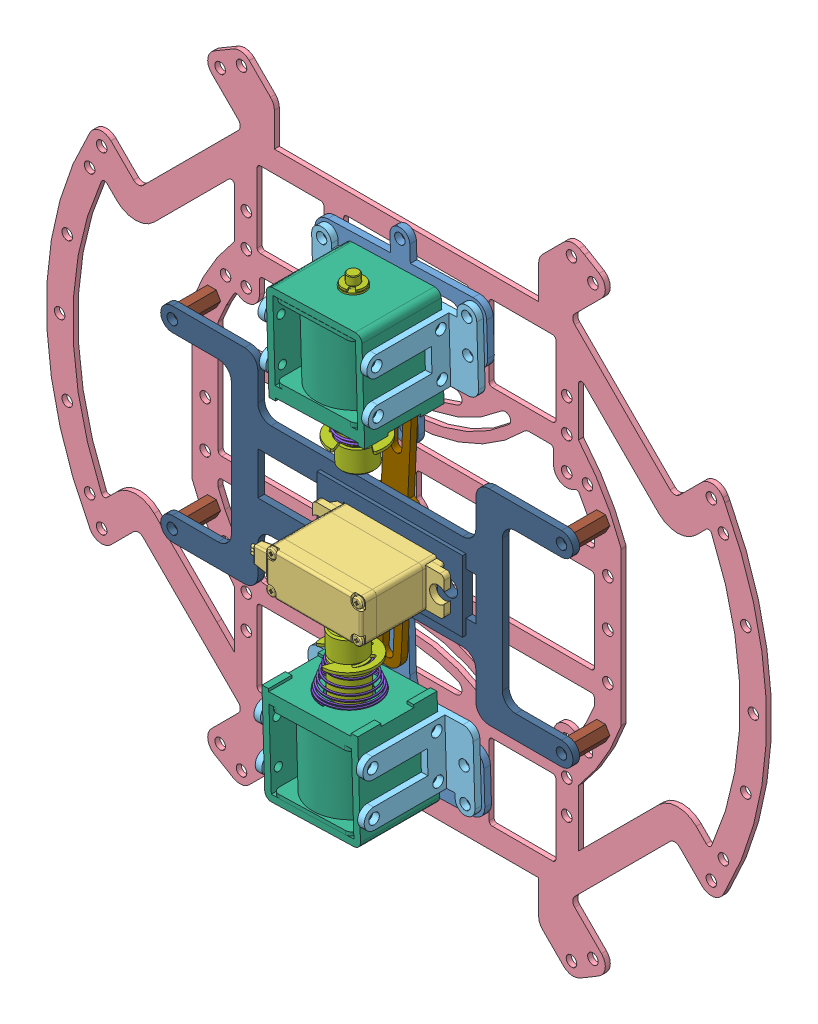
SolidWorks assembly Aimbot-S Test, configuration Default. Lengths in mm.
Overall size (218 192.21 37.61).
21 component instances, 11 part files, 45 mates.
Components (placement in the parent):
- Aimbot Swing-1: Aimbot Swing [Default] at (65.0684 191.5331 171.8045) x (0.999536 0.030468 0) z (0.030468 -0.999536 0) size (52 2 56)
- Sero Adaptor-4: Sero Adaptor [Default] at (64.9466 122.5312 173.8045) x (0.047484 0.998872 0) z (-0.998872 0.047484 0) size (9.1 5 34)
- Servo 2-2: Servo 2 [Default] at (58.4466 116.1312 207.9045) x (1 0 0) z (0 1 0) size (41.92 34.11 12.86)
- Aimbot Mid-1: Aimbot Mid [Default] at (64.9466 122.5312 170.3045) size (218 192.21 1.5)
- CB1029 Kicker Stand-1: CB1029 Kicker Stand [Default] at (49.6459 75.5772 197.7045) x (0 0 -1) z (-0.999536 -0.030468 0) size (26.9 23.5 50)
- CB1029 Kicker Stand-2: CB1029 Kicker Stand [Default] at (80.2472 169.4853 197.7045) x (0 0 -1) z (0.999536 0.030468 0) size (26.9 23.5 50)
- INPUT kicker-3: INPUT kicker [Default] at (61.4457 70.5378 188.2528) x (0.999536 0.030468 0) z (0 0 1) size (29 49.3 24.1)
  - Part5^w_cb1029A-1: Part5^w_cb1029A [Default] at (2.8592 11.2966 11.7516) size (29 29.6 24.1)
  - Part1^w_cb1029A_pl-1: Part1^w_cb1029A_pl [Default] at (2.8592 29.7903 -0.2484) x (-0.794223 0 -0.607626) z (0 1 0) size (16 14.34 49.3)
  - w_21053081-1: w_21053081 [Default] at (2.8631 13.1716 -0.3303) size (16.55 9.4 16.57)
- INPUT kicker-4: INPUT kicker [Default] at (68.4474 174.5247 188.2528) x (-0.999536 -0.030468 0) z (0 0 1) size (29 49.3 24.1)
  - Part5^w_cb1029A-1: Part5^w_cb1029A [Default] at (2.8592 11.2966 11.7516) size (29 29.6 24.1)
  - Part1^w_cb1029A_pl-1: Part1^w_cb1029A_pl [Default] at (2.8592 29.7903 -0.2484) x (-0.794223 0 -0.607626) z (0 1 0) size (16 14.34 49.3)
  - w_21053081-1: w_21053081 [Default] at (2.8631 13.1716 -0.3303) size (16.55 9.4 16.57)
- Aimbot Lever-2: Aimbot Lever [Default] at (66.6085 157.4918 173.8045) x (-0.047484 -0.998872 0) z (-0.998872 0.047484 0) size (78 2 32)
- Aimbot Swing-4: Aimbot Swing [Default] at (64.8247 53.5294 171.8045) x (-0.999536 -0.030468 0) z (-0.030468 0.999536 0) size (52 2 56)
- Servo Stand-1: Servo Stand [Default] at (6.0347 95.0602 181.8045) size (124.82 61.94 3)
- 10mm Standoff-1: 10mm Standoff [默认] at (123.8585 150.0023 171.8045) x (1 0 0) z (0 -1 0) size (5.31 10 4.6)
- 10mm Standoff-2: 10mm Standoff [默认] at (123.8585 95.0602 171.8045) x (1 0 0) z (0 -1 0) size (5.31 10 4.6)
- 10mm Standoff-3: 10mm Standoff [默认] at (6.0347 150.0023 171.8045) x (1 0 0) z (0 -1 0) size (5.31 10 4.6)
- 10mm Standoff-4: 10mm Standoff [默认] at (6.0347 95.0602 171.8045) x (1 0 0) z (0 -1 0) size (5.31 10 4.6)
Mates (geometry in assembly coordinates):
- Coincident15: coincident anti-aligned: plane of Sero Adaptor-4 through (79.4302 121.8427 173.8045) normal (0 0 1); plane of Servo 2-2 through (62.1259 125.3519 173.8045) normal (0 0 -1)
- Concentric35: concentric anti-aligned: cylinder of Servo 2-2 through (64.9466 122.5312 179.1045) axis (0 0 -1) radius 0.925; cylinder of Aimbot Mid-1 through (64.9466 122.5312 50.2343) axis (0 0 1) radius 1.6
- Concentric36: concentric aligned: cylinder of Aimbot Swing-1 through (64.9466 195.5312 168.3045) axis (0 0 1) radius 1.6; cylinder of Aimbot Mid-1 through (64.9466 195.5312 170.3045) axis (0 0 1) radius 1.5
- Coincident17: coincident anti-aligned: plane of Aimbot Swing-1 through (65.0684 191.5331 173.8045) normal (0 0 1); plane of CB1029 Kicker Stand-2 through (80.3386 166.4867 173.8045) normal (0 0 -1)
- Coincident20: coincident anti-aligned: plane of Aimbot Swing-1 through (65.0684 191.5331 171.8045) normal (0 0 -1); plane of Aimbot Mid-1 through (64.9466 122.5312 171.8045) normal (0 0 1)
- Coincident21: coincident anti-aligned: plane of CB1029 Kicker Stand-2 through (51.2607 168.6018 197.7045) normal (0.999536 0.030468 0); plane of INPUT kicker-4/Part5^w_cb1029A-1 through (50.6818 187.5929 176.0045) normal (-0.999536 -0.030468 0)
- Concentric45: concentric aligned: cylinder of CB1029 Kicker Stand-2 through (81.8502 182.5402 178.3045) axis (-0.999536 -0.030468 0) radius 1.6; cylinder of INPUT kicker-4/Part5^w_cb1029A-1 through (79.8512 182.4793 178.3045) axis (-0.999536 -0.030468 0) radius 1.25
- Concentric46: concentric aligned: cylinder of CB1029 Kicker Stand-2 through (82.2463 169.5463 197.7045) axis (-0.999536 -0.030468 0) radius 1.6; cylinder of INPUT kicker-4/Part5^w_cb1029A-1 through (80.2472 169.4853 197.7045) axis (-0.999536 -0.030468 0) radius 1.25
- Coincident22: coincident anti-aligned: plane of CB1029 Kicker Stand-1 through (78.6325 76.4607 197.7045) normal (-0.999536 -0.030468 0); plane of INPUT kicker-3/Part5^w_cb1029A-1 through (79.2113 57.4695 176.0045) normal (0.999536 0.030468 0)
- Concentric47: concentric aligned: cylinder of CB1029 Kicker Stand-1 through (48.0429 62.5223 197.7045) axis (0.999536 0.030468 0) radius 1.6; cylinder of INPUT kicker-3/Part5^w_cb1029A-1 through (50.042 62.5832 197.7045) axis (0.999536 0.030468 0) radius 1.25
- Concentric48: concentric aligned: cylinder of CB1029 Kicker Stand-1 through (47.6468 75.5162 178.3045) axis (0.999536 0.030468 0) radius 1.6; cylinder of INPUT kicker-3/Part5^w_cb1029A-1 through (49.6459 75.5772 178.3045) axis (0.999536 0.030468 0) radius 1.25
- Concentric49: concentric aligned: cylinder of Aimbot Swing-1 through (87.2106 187.2057 173.8045) axis (0 0 -1) radius 1.6; cylinder of CB1029 Kicker Stand-2 through (87.2106 187.2057 183.8045) axis (0 0 -1) radius 1.6
- Concentric50: concentric aligned: cylinder of Aimbot Swing-1 through (43.231 185.8651 173.8045) axis (0 0 -1) radius 1.6; cylinder of CB1029 Kicker Stand-2 through (43.231 185.8651 183.8045) axis (0 0 -1) radius 1.6
- Concentric51: concentric aligned: cylinder of Aimbot Swing-1 through (43.5357 175.8698 173.8045) axis (0 0 -1) radius 1.6; cylinder of CB1029 Kicker Stand-2 through (43.5357 175.8698 183.8045) axis (0 0 -1) radius 1.6
- Concentric52: concentric aligned: cylinder of Aimbot Swing-1 through (87.5152 177.2103 173.8045) axis (0 0 -1) radius 1.6; cylinder of CB1029 Kicker Stand-2 through (87.5152 177.2103 183.8045) axis (0 0 -1) radius 1.6
- Concentric57: concentric aligned: cylinder of Sero Adaptor-4 through (78.9308 121.8665 171.8045) axis (0 0 1) radius 0.5; cylinder of Aimbot Lever-2 through (78.9308 121.8665 91.3423) axis (0 0 1) radius 0.5
- Concentric58: concentric aligned: cylinder of Sero Adaptor-4 through (74.4359 122.0801 171.8045) axis (0 0 1) radius 0.5; cylinder of Aimbot Lever-2 through (74.4359 122.0801 91.3423) axis (0 0 1) radius 0.5
- Coincident24: coincident anti-aligned: plane of Aimbot Swing-1 through (65.0684 191.5331 173.8045) normal (0 0 1); plane of Aimbot Lever-2 through (66.6085 157.4918 173.8045) normal (0 0 -1)
- Concentric59: concentric aligned: cylinder of Aimbot Mid-1 through (64.9466 122.5312 50.2343) axis (0 0 1) radius 1.6; cylinder of Aimbot Lever-2 through (64.9466 122.5312 148.3486) axis (0 0 1) radius 5
- Coincident25: coincident anti-aligned: plane of Sero Adaptor-4 through (79.4302 121.8427 173.8045) normal (0 0 1); plane of Aimbot Lever-2 through (66.6085 157.4918 173.8045) normal (0 0 -1)
- Parallel1: parallel anti-aligned: plane of Sero Adaptor-4 through (79.4302 121.8427 171.8045) normal (0 0 -1); plane of Aimbot Mid-1 through (64.9466 122.5312 171.8045) normal (0 0 1)
- Coincident28: coincident anti-aligned: plane of Aimbot Mid-1 through (64.9466 122.5312 171.8045) normal (0 0 1); plane of Aimbot Swing-4 through (64.8247 53.5294 171.8045) normal (0 0 -1)
- Concentric60: concentric aligned: cylinder of CB1029 Kicker Stand-1 through (42.6826 57.8568 183.8045) axis (0 0 -1) radius 1.6; cylinder of Aimbot Swing-4 through (42.6826 57.8568 173.8045) axis (0 0 -1) radius 1.6
- Concentric61: concentric aligned: cylinder of CB1029 Kicker Stand-1 through (86.6622 59.1973 183.8045) axis (0 0 -1) radius 1.6; cylinder of Aimbot Swing-4 through (86.6622 59.1973 173.8045) axis (0 0 -1) radius 1.6
- Concentric62: concentric aligned: cylinder of Aimbot Mid-1 through (64.9466 49.5312 170.3045) axis (0 0 1) radius 1.5; cylinder of Aimbot Swing-4 through (64.9466 49.5312 168.3045) axis (0 0 1) radius 1.6
- Coincident29: coincident anti-aligned: plane of Aimbot Mid-1 through (64.9466 122.5312 171.8045) normal (0 0 1); plane of Aimbot Swing-4 through (64.8247 53.5294 171.8045) normal (0 0 -1)
- Concentric63: concentric aligned: cylinder of CB1029 Kicker Stand-1 through (86.6622 59.1973 183.8045) axis (0 0 -1) radius 1.6; cylinder of Aimbot Swing-4 through (86.6622 59.1973 173.8045) axis (0 0 -1) radius 1.6
- Concentric64: concentric aligned: cylinder of CB1029 Kicker Stand-1 through (86.3575 69.1927 183.8045) axis (0 0 -1) radius 1.6; cylinder of Aimbot Swing-4 through (86.3575 69.1927 173.8045) axis (0 0 -1) radius 1.6
- Coincident30: coincident anti-aligned: circle of Aimbot Mid-1; cylinder of Servo Stand-1 through (123.8585 150.0023 183.8045) axis (0 0 -1) radius 1.6
- Coincident31: coincident aligned: circle of Aimbot Mid-1; cylinder of Servo Stand-1 through (123.8585 95.0602 183.8045) axis (0 0 -1) radius 1.6
- Concentric65: concentric anti-aligned: cylinder of Aimbot Mid-1 through (6.0347 95.0602 170.3045) axis (0 0 1) radius 1.6; cylinder of Servo Stand-1 through (6.0347 95.0602 183.8045) axis (0 0 -1) radius 1.6
- Parallel2: parallel aligned: cylinder of Aimbot Mid-1 through (3.9986 136.531 171.8045) axis (0 0 -1) radius 1.6; cylinder of Servo Stand-1 through (6.0347 150.0023 183.8045) axis (0 0 -1) radius 1.6
- Parallel3: parallel anti-aligned: cylinder of Servo 2-2 through (90.9279 122.5312 188.3045) axis (0 0 -1) radius 2.5; cylinder of Servo Stand-1 through (90.9266 122.5312 153.6442) axis (0 0 1) radius 2.5
- Concentric68: concentric anti-aligned: cylinder of Servo 2-2 through (54.8653 122.5312 188.3045) axis (0 0 -1) radius 2.5; cylinder of Servo Stand-1 through (54.8656 122.5312 173.8045) axis (0 0 1) radius 2.5
- Coincident34: coincident anti-aligned: plane of Servo 2-2 through (87.0535 116.7167 184.8045) normal (0 0 -1); plane of Servo Stand-1 through (6.0347 95.0602 184.8045) normal (0 0 1)
- Coincident35: coincident anti-aligned: plane of Servo Stand-1 through (6.0347 95.0602 181.8045) normal (0 0 -1); plane of 10mm Standoff-3 through (6.0347 150.0023 181.8045) normal (0 0 1)
- Concentric69: concentric aligned: cylinder of Servo Stand-1 through (6.0347 150.0023 183.8045) axis (0 0 -1) radius 1.6; cylinder of 10mm Standoff-3 through (6.0347 150.0023 176.8045) axis (0 0 -1) radius 1.5
- Coincident36: coincident anti-aligned: plane of Servo Stand-1 through (6.0347 95.0602 181.8045) normal (0 0 -1); plane of 10mm Standoff-4 through (6.0347 95.0602 181.8045) normal (0 0 1)
- Concentric70: concentric aligned: cylinder of Servo Stand-1 through (6.0347 95.0602 183.8045) axis (0 0 -1) radius 1.6; cylinder of 10mm Standoff-4 through (6.0347 95.0602 176.8045) axis (0 0 -1) radius 1.5
- Coincident37: coincident anti-aligned: plane of Servo Stand-1 through (6.0347 95.0602 181.8045) normal (0 0 -1); plane of 10mm Standoff-2 through (123.8585 95.0602 181.8045) normal (0 0 1)
- Concentric71: concentric aligned: cylinder of Servo Stand-1 through (123.8585 95.0602 183.8045) axis (0 0 -1) radius 1.6; cylinder of 10mm Standoff-2 through (123.8585 95.0602 176.8045) axis (0 0 -1) radius 1.5
- Coincident38: coincident: plane of Servo Stand-1 through (6.0347 95.0602 181.8045) normal (0 0 -1); line of 10mm Standoff-1 through (122.5306 147.7023 181.8045) axis (1 0 0)
- Concentric72: concentric aligned: cylinder of Servo Stand-1 through (123.8585 150.0023 183.8045) axis (0 0 -1) radius 1.6; cylinder of 10mm Standoff-1 through (123.8585 150.0023 176.8045) axis (0 0 -1) radius 1.5
- Slot1: slot aligned: cylinder of Aimbot Swing-1 through (66.3024 151.0519 181.8045) axis (0 0 -1) radius 1.6; plane of Aimbot Lever-2 through (67.4945 142.4327 185.8045) normal (-0.998872 0.047484 0); cylinder of Aimbot Lever-2 through (66.6085 157.4918 185.8045) axis (0 0 -1) radius 1.6
- Slot2: slot aligned: cylinder of Aimbot Swing-4 through (63.5908 94.0106 181.8045) axis (0 0 -1) radius 1.6; plane of Aimbot Lever-2 through (65.5951 102.4778 185.8045) normal (-0.998872 0.047484 0); cylinder of Aimbot Lever-2 through (63.9969 102.5538 185.8045) axis (0 0 -1) radius 1.6
